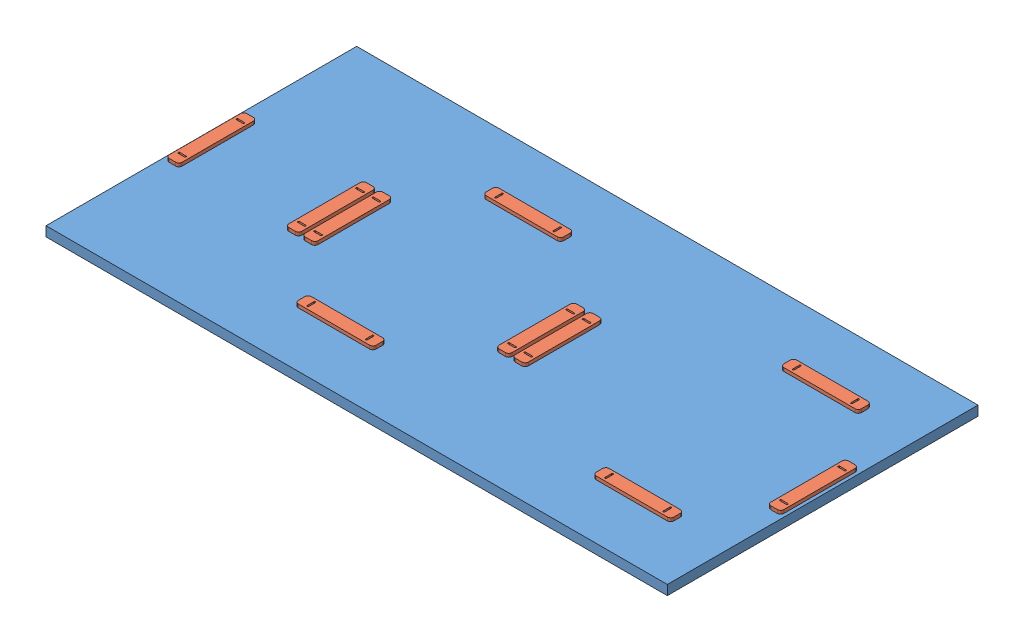
SolidWorks assembly BASE, configuration Default. Lengths in mm.
Overall size (1219.2 25.65 609.6).
11 component instances, 2 part files, 33 mates.
Components (placement in the parent):
- PLYWOOD, BASE-1: PLYWOOD, BASE [Default] at origin size (1219.2 19.05 609.6)
- SPACER, BASE-1: SPACER, BASE [Default] at (590.55 19.05 0) size (25.4 6.6 152.4)
- SPACER, BASE-17: SPACER, BASE [Default] at (57.15 19.05 0) size (25.4 6.6 152.4)
- SPACER, BASE-18: SPACER, BASE [Default] at (89.154 19.05 0) size (25.4 6.6 152.4)
- SPACER, BASE-20: SPACER, BASE [Default] at (-323.342 19.05 0) size (25.4 6.6 152.4)
- SPACER, BASE-21: SPACER, BASE [Default] at (-355.346 19.05 0) size (25.4 6.6 152.4)
- SPACER, BASE-22: SPACER, BASE [Default] at (-590.042 19.05 0) size (25.4 6.6 152.4)
- SPACER, BASE-24: SPACER, BASE [Default] at (431.8 19.05 -184.15) x (0 0 -1) z (1 0 0) size (25.4 6.6 152.4)
- SPACER, BASE-27: SPACER, BASE [Default] at (-152.4 19.05 -184.15) x (0 0 -1) z (1 0 0) size (25.4 6.6 152.4)
- SPACER, BASE-29: SPACER, BASE [Default] at (431.8 25.654 184.15) x (0 0 1) z (1 0 0) size (25.4 6.6 152.4)
- SPACER, BASE-30: SPACER, BASE [Default] at (-152.4 25.654 184.15) x (0 0 1) z (1 0 0) size (25.4 6.6 152.4)
Mates (geometry in assembly coordinates):
- Coincident1: coincident aligned: plane of PLYWOOD, BASE-1 through (0 0 0) normal (0 0 1); plane of assembly through (0 0 0) normal (0 0 1)
- Coincident2: coincident aligned: plane of PLYWOOD, BASE-1 through (0 0 0) normal (0 1 0); plane of assembly through (0 0 0) normal (0 1 0)
- Coincident3: coincident aligned: plane of PLYWOOD, BASE-1 through (0 0 0) normal (1 0 0); plane of assembly through (0 0 0) normal (1 0 0)
- Coincident4: coincident aligned: plane of SPACER, BASE-1 through (590.55 19.05 0) normal (0 0 1); plane of assembly through (0 0 0) normal (0 0 1)
- Coincident5: coincident anti-aligned: plane of PLYWOOD, BASE-1 through (0 19.05 0) normal (0 1 0); plane of SPACER, BASE-1 through (590.55 19.05 0) normal (0 -1 0)
- Coincident6: coincident aligned: plane of SPACER, BASE-17 through (57.15 19.05 0) normal (0 0 1); plane of assembly through (0 0 0) normal (0 0 1)
- Coincident7: coincident anti-aligned: plane of PLYWOOD, BASE-1 through (0 19.05 0) normal (0 1 0); plane of SPACER, BASE-17 through (57.15 19.05 0) normal (0 -1 0)
- Coincident8: coincident aligned: plane of SPACER, BASE-18 through (89.154 19.05 0) normal (0 0 1); plane of assembly through (0 0 0) normal (0 0 1)
- Coincident9: coincident anti-aligned: plane of PLYWOOD, BASE-1 through (0 19.05 0) normal (0 1 0); plane of SPACER, BASE-18 through (89.154 19.05 0) normal (0 -1 0)
- Distance1: distance = 6.35 mm aligned: plane of PLYWOOD, BASE-1 through (609.6 19.05 -304.8) normal (1 0 0); plane of SPACER, BASE-1 through (603.25 25.654 -76.2) normal (1 0 0)
- Distance2: distance = 533.4 mm aligned: plane of SPACER, BASE-17 through (69.85 25.654 -76.2) normal (1 0 0); plane of SPACER, BASE-1 through (603.25 25.654 -76.2) normal (1 0 0)
- Distance3: distance = 6.604 mm anti-aligned: plane of SPACER, BASE-17 through (69.85 25.654 -76.2) normal (1 0 0); plane of SPACER, BASE-18 through (76.454 25.654 -76.2) normal (-1 0 0)
- Coincident18: coincident aligned: plane of SPACER, BASE-20 through (-323.342 19.05 0) normal (0 0 1); plane of assembly through (0 0 0) normal (0 0 1)
- Coincident20: coincident anti-aligned: plane of PLYWOOD, BASE-1 through (0 19.05 0) normal (0 1 0); plane of SPACER, BASE-20 through (-323.342 19.05 0) normal (0 -1 0)
- Coincident21: coincident anti-aligned: plane of PLYWOOD, BASE-1 through (0 19.05 0) normal (0 1 0); plane of SPACER, BASE-21 through (-355.346 19.05 0) normal (0 -1 0)
- Coincident22: coincident anti-aligned: plane of PLYWOOD, BASE-1 through (0 19.05 0) normal (0 1 0); plane of SPACER, BASE-22 through (-590.042 19.05 0) normal (0 -1 0)
- Coincident23: coincident aligned: plane of SPACER, BASE-21 through (-355.346 19.05 0) normal (0 0 1); plane of assembly through (0 0 0) normal (0 0 1)
- Coincident24: coincident aligned: plane of SPACER, BASE-22 through (-590.042 19.05 0) normal (0 0 1); plane of assembly through (0 0 0) normal (0 0 1)
- Distance4: distance = 6.604 mm anti-aligned: plane of SPACER, BASE-21 through (-342.646 25.654 -76.2) normal (1 0 0); plane of SPACER, BASE-20 through (-336.042 25.654 -76.2) normal (-1 0 0)
- Distance5: distance = 266.7 mm aligned: plane of SPACER, BASE-22 through (-602.742 25.654 -76.2) normal (-1 0 0); plane of SPACER, BASE-20 through (-336.042 25.654 -76.2) normal (-1 0 0)
- Distance6: distance = 1205.992 mm anti-aligned: plane of SPACER, BASE-22 through (-602.742 25.654 -76.2) normal (-1 0 0); plane of SPACER, BASE-1 through (603.25 25.654 -76.2) normal (1 0 0)
- Distance7: distance = 184.15 mm anti-aligned: plane of SPACER, BASE-24 through (431.8 19.05 -184.15) normal (0 0 -1); plane of assembly through (0 0 0) normal (0 0 1)
- Coincident29: coincident anti-aligned: plane of PLYWOOD, BASE-1 through (0 19.05 0) normal (0 1 0); plane of SPACER, BASE-24 through (431.8 19.05 -184.15) normal (0 -1 0)
- Distance8: distance = 177.8 mm aligned: plane of PLYWOOD, BASE-1 through (609.6 19.05 -304.8) normal (1 0 0); plane of SPACER, BASE-24 through (431.8 19.05 -184.15) normal (1 0 0)
- Coincident31: coincident anti-aligned: plane of PLYWOOD, BASE-1 through (0 19.05 0) normal (0 1 0); plane of SPACER, BASE-27 through (-152.4 19.05 -184.15) normal (0 -1 0)
- Distance9: distance = 184.15 mm anti-aligned: plane of SPACER, BASE-27 through (-152.4 19.05 -184.15) normal (0 0 -1); plane of assembly through (0 0 0) normal (0 0 1)
- Distance15: distance = 762 mm aligned: plane of PLYWOOD, BASE-1 through (609.6 19.05 -304.8) normal (1 0 0); plane of SPACER, BASE-27 through (-152.4 19.05 -184.15) normal (1 0 0)
- Coincident33: coincident aligned: plane of SPACER, BASE-24 through (431.8 19.05 -184.15) normal (1 0 0); plane of SPACER, BASE-29 through (431.8 25.654 184.15) normal (1 0 0)
- Coincident34: coincident anti-aligned: plane of PLYWOOD, BASE-1 through (0 19.05 0) normal (0 1 0); plane of SPACER, BASE-29 through (431.8 19.05 184.15) normal (0 -1 0)
- Distance17: distance = 184.15 mm aligned: plane of SPACER, BASE-29; plane of assembly through (0 0 0) normal (0 0 1)
- Coincident36: coincident aligned: plane of SPACER, BASE-27 through (-152.4 19.05 -184.15) normal (1 0 0); plane of SPACER, BASE-30 through (-152.4 25.654 184.15) normal (1 0 0)
- Coincident37: coincident anti-aligned: plane of PLYWOOD, BASE-1 through (0 19.05 0) normal (0 1 0); plane of SPACER, BASE-30 through (-152.4 19.05 184.15) normal (0 -1 0)
- Distance18: distance = 184.15 mm aligned: plane of SPACER, BASE-30; plane of assembly through (0 0 0) normal (0 0 1)
